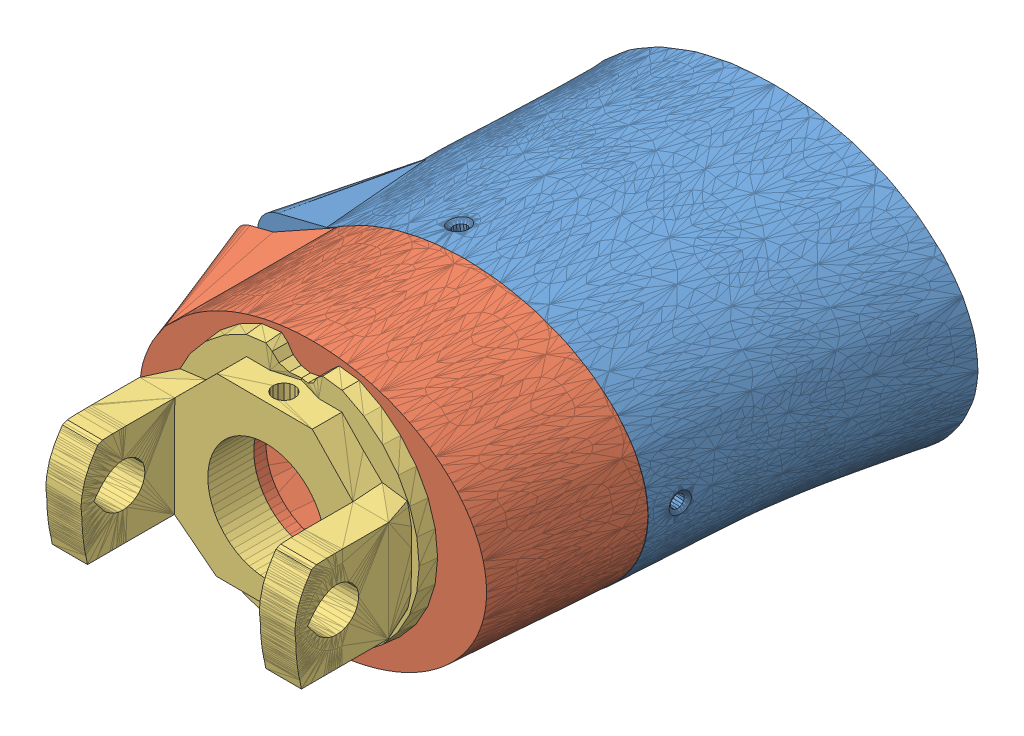
SolidWorks assembly Fixed Wrist_test, configuration Default. Lengths in mm.
Overall size (78.57 52.81 107.91).
3 component instances, 3 part files, 0 mates.
Components (placement in the parent):
- Rotawrist1V4_1-1: Rotawrist1V4_1 [Default] at (-41.5785 2.8378 -7.6893) size (78.57 52.81 54.68)
- RotaWrist2V3_1-1: RotaWrist2V3_1 [Default] at (-44.0484 3.5992 74.4289) x (-0.999998 0.000853 -0.001889) z (0.001889 0.000054 -0.999998) size (71.94 48.58 37.97)
- RotaWrist3V3_1-1: RotaWrist3V3_1 [Default] at (-43.4074 4.3051 74.4302) x (0.999995 -0.002526 0.001889) z (-0.001889 -0.000054 0.999998) size (47.2 44.33 25.75)
